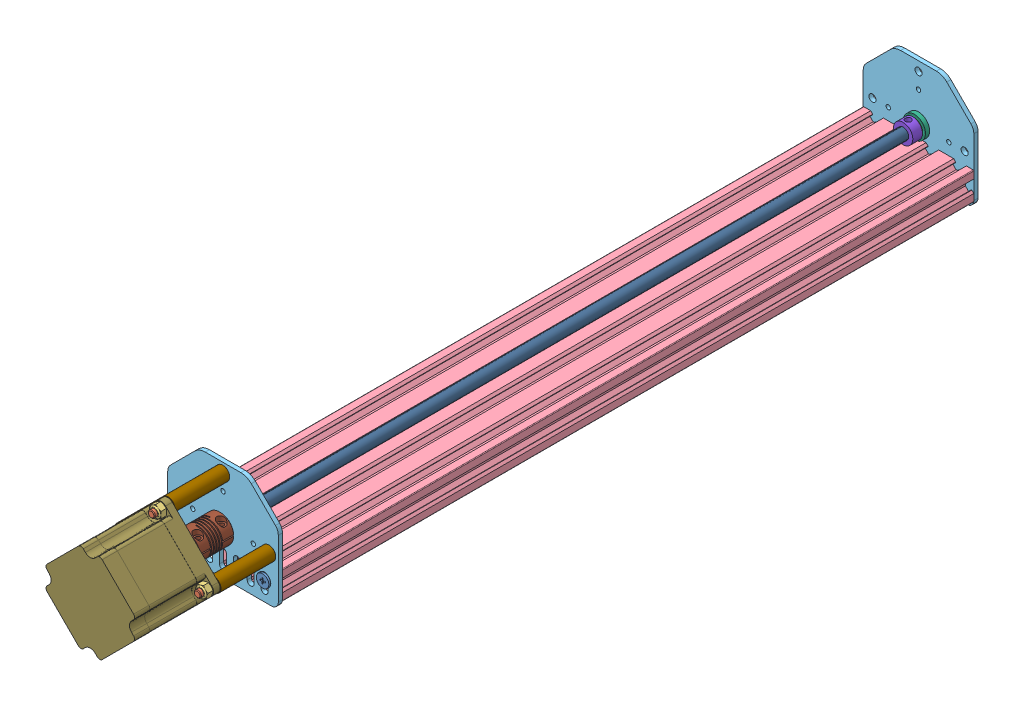
SolidWorks assembly Nema 23 V Slot Lead Screw Driven Actuator, configuration Default. Lengths in mm.
Overall size (80.26 79.88 603.4).
25 component instances, 12 part files, 55 mates.
Components (placement in the parent):
- Self Tapping Screw-1: Self Tapping Screw [Default] at (-30 0 503) x (-1 0 0) z (0 1 0) size (9.6 20.4 9.6)
- Self Tapping Screw-3: Self Tapping Screw [Default] at (30 0 503) x (-1 0 0) z (0 1 0) size (9.6 20.4 9.6)
- Self Tapping Screw-4: Self Tapping Screw [Default] at (30 0 -3) x (1 0 0) z (0 1 0) size (9.6 20.4 9.6)
- Self Tapping Screw-6: Self Tapping Screw [Default] at (-30 0 -3) x (1 0 0) z (0 1 0) size (9.6 20.4 9.6)
- Low Profile Screw M5-11: Low Profile Screw M5 [M5 x 55] at (33.333 18.57 555) x (0 0 1) z (-1 0 0) size (56.62 9 9)
- Low Profile Screw M5-12: Low Profile Screw M5 [M5 x 55] at (0 51.903 555) x (0 0 1) z (-1 0 0) size (56.62 9 9)
- Low Profile Screw M5-13: Low Profile Screw M5 [M5 x 55] at (-33.333 18.57 555) x (0 0 1) z (-1 0 0) size (56.62 9 9)
- Nylon Insert Lock Nut M5-3: Nylon Insert Lock Nut M5 [Default] at (33.333 18.57 547.8) x (0.963541 -0.267562 0) z (-0.267562 -0.963541 0) size (8 5 9.24)
- Nylon Insert Lock Nut M5-4: Nylon Insert Lock Nut M5 [Default] at (0 51.903 547.8) x (1 0 0) z (0 -1 0) size (8 5 9.24)
- Nylon Insert Lock Nut M5-5: Nylon Insert Lock Nut M5 [Default] at (-33.333 18.57 547.8) x (1 0 0) z (0 -1 0) size (8 5 9.24)
- V-Slot 20x80x500 Linear Rail-1: V-Slot 20x80x500 Linear Rail [Default] x (0 -1 0) z (0 0 1) size (20 80 500)
- Threaded Rod Plate Nema 23-2: Threaded Rod Plate Nema 23 [Default] at (0 18.57 503) x (-1 0 0) z (0 -1 0) size (80 3 72.5)
- Threaded Rod Plate Nema 23-3: Threaded Rod Plate Nema 23 [Default] at (0 18.57 -3) x (1 0 0) z (0 -1 0) size (80 3 72.5)
- Ball Bearing 8 x 16 x 5-1: Ball Bearing 8 x 16 x 5 [Default] at (0 18.57 0.5) x (0 0 1) z (-0.957169 -0.289529 0) size (5 16 16)
- Ball Bearing 8 x 16 x 5-2: Ball Bearing 8 x 16 x 5 [Default] at (0 18.57 499.5) x (0 0 1) z (0.959032 0.283297 0) size (5 16 16)
- Shim Washer 8mm-1: Shim Washer 8mm [Default] at (0 18.57 3) x (0.504051 0.863674 0) z (0.863674 -0.504051 0) size (11.8 1.15 11.8)
- Shim Washer 8mm-2: Shim Washer 8mm [Default] at (0 18.57 497) x (-0.37401 -0.927425 0) z (0.927425 -0.37401 0) size (11.8 1.15 11.8)
- Lock Collar 8mm-1: Lock Collar 8mm [Default] at (0 18.57 488.85) size (14 14 7)
- Lock Collar 8mm-2: Lock Collar 8mm [Default] at (0 18.57 4.15) size (14 14 7)
- Aluminum Spacer 40mm-4: Aluminum Spacer 40mm [Default] at (-33.333 18.57 503) x (0.854977 0.518666 0) z (0 0 1) size (10 10 40)
- Aluminum Spacer 40mm-5: Aluminum Spacer 40mm [Default] at (0 51.903 503) x (0.998694 -0.051087 0) z (0 0 1) size (10 10 40)
- Aluminum Spacer 40mm-3: Aluminum Spacer 40mm [Default] at (33.333 18.57 503) x (0.890209 0.455552 0) z (0 0 1) size (10 10 40)
- 8mm leadscrew 520mm-1: 8mm leadscrew 520mm [Default] at (0 18.57 -3) size (8 8 520)
- Flexible Coupling 0.25in x 8mm-1: Flexible Coupling 0.25in x 8mm [Default] at (0 18.57 530) x (0.999321 0.036837 0) z (0 0 1) size (21.03 20 25)
- Nema 23 Stepper Motor-1: Nema 23 Stepper Motor [Default] at (0 18.57 543) x (0.707107 -0.707107 0) z (0 0 -1) size (56.4 56.4 76.6)
Mates (geometry in assembly coordinates):
- Coincident4: coincident anti-aligned: plane of V-Slot 20x80x500 Linear Rail-1 through (0 0 500) normal (0 0 1); plane of Threaded Rod Plate Nema 23-2 through (35 -8.93 500) normal (0 0 -1)
- Distance4: distance = 3.93 mm aligned: plane of V-Slot 20x80x500 Linear Rail-1 through (0 -10 500) normal (0 -1 0); plane of Threaded Rod Plate Nema 23-2 through (-35 -13.93 500) normal (0 -1 0)
- Coincident6: coincident anti-aligned: plane of V-Slot 20x80x500 Linear Rail-1 through (0 0 0) normal (1 0 0); plane of Threaded Rod Plate Nema 23-2 through (0 18.57 503) normal (-1 0 0)
- Coincident7: coincident anti-aligned: plane of V-Slot 20x80x500 Linear Rail-1 through (0 0 0) normal (0 0 -1); plane of Threaded Rod Plate Nema 23-3 through (-35 -8.93 0) normal (0 0 1)
- Distance3: distance = 3.93 mm aligned: plane of V-Slot 20x80x500 Linear Rail-1 through (0 -10 500) normal (0 -1 0); plane of Threaded Rod Plate Nema 23-3 through (35 -13.93 0) normal (0 -1 0)
- Coincident9: coincident aligned: plane of V-Slot 20x80x500 Linear Rail-1 through (0 0 0) normal (1 0 0); plane of Threaded Rod Plate Nema 23-3 through (0 18.57 -3) normal (1 0 0)
- Concentric1: concentric anti-aligned: cylinder of Threaded Rod Plate Nema 23-3 through (0 18.57 0) axis (0 0 -1) radius 5.5; cylinder of Ball Bearing 8 x 16 x 5-1 through (0 18.57 0.5) axis (0 0 1) radius 8
- Coincident10: coincident anti-aligned: plane of Threaded Rod Plate Nema 23-3 through (0 18.57 -2) normal (0 0 1); plane of Ball Bearing 8 x 16 x 5-1 through (-2.0846 25.4616 -2) normal (0 0 -1)
- Concentric2: concentric anti-aligned: cylinder of Threaded Rod Plate Nema 23-2 through (0 18.57 502) axis (0 0 -1) radius 8.025; cylinder of Ball Bearing 8 x 16 x 5-2 through (0 18.57 499.5) axis (0 0 1) radius 8
- Coincident11: coincident anti-aligned: plane of Threaded Rod Plate Nema 23-2 through (0 18.57 502) normal (0 0 -1); plane of Ball Bearing 8 x 16 x 5-2 through (2.0397 11.665 502) normal (0 0 1)
- Concentric3: concentric anti-aligned: cylinder of Ball Bearing 8 x 16 x 5-1 through (0 18.57 0.5) axis (0 0 1) radius 5.1; cylinder of Shim Washer 8mm-1 through (0 18.57 4.15) axis (0 0 -1) radius 4.25
- Coincident12: coincident anti-aligned: plane of Ball Bearing 8 x 16 x 5-1 through (-1.1581 22.3987 3) normal (0 0 1); plane of Shim Washer 8mm-1 through (0 18.57 3) normal (0 0 -1)
- Concentric4: concentric aligned: cylinder of Ball Bearing 8 x 16 x 5-2 through (0 18.57 499.5) axis (0 0 1) radius 4; cylinder of Shim Washer 8mm-2 through (0 18.57 495.85) axis (0 0 1) radius 4.25
- Coincident13: coincident anti-aligned: plane of Ball Bearing 8 x 16 x 5-2 through (1.1332 14.7339 497) normal (0 0 -1); plane of Shim Washer 8mm-2 through (0 18.57 497) normal (0 0 1)
- Concentric5: concentric anti-aligned: cylinder of Shim Washer 8mm-2 through (0 18.57 495.85) axis (0 0 1) radius 5.9; cylinder of Lock Collar 8mm-1 through (0 18.57 495.85) axis (0 0 -1) radius 4
- Coincident14: coincident anti-aligned: plane of Shim Washer 8mm-2 through (0 18.57 495.85) normal (0 0 -1); plane of Lock Collar 8mm-1 through (0 18.57 495.85) normal (0 0 1)
- Concentric6: concentric aligned: cylinder of Shim Washer 8mm-1 through (0 18.57 4.15) axis (0 0 -1) radius 4.25; cylinder of Lock Collar 8mm-2 through (0 18.57 11.15) axis (0 0 -1) radius 4
- Coincident15: coincident anti-aligned: plane of Shim Washer 8mm-1 through (0 18.57 4.15) normal (0 0 1); plane of Lock Collar 8mm-2 through (0 18.57 4.15) normal (0 0 -1)
- Parallel1: parallel aligned: plane of Lock Collar 8mm-1 through (0 18.57 488.85) normal (0 1 0); plane of assembly through (0 0 0) normal (0 1 0)
- Parallel2: parallel aligned: plane of Lock Collar 8mm-2 through (0 18.57 4.15) normal (0 1 0); plane of assembly through (0 0 0) normal (0 1 0)
- Concentric7: concentric anti-aligned: cylinder of V-Slot 20x80x500 Linear Rail-1 through (-30 0 500) axis (0 0 -1) radius 2.1; cylinder of Self Tapping Screw-1 through (-30 0 484) axis (0 0 1) radius 2.425
- Coincident18: coincident anti-aligned: plane of Threaded Rod Plate Nema 23-2 through (35 -8.93 503) normal (0 0 1); plane of Self Tapping Screw-1 through (-27.575 0 503) normal (0 0 -1)
- Concentric91: concentric anti-aligned: cylinder of V-Slot 20x80x500 Linear Rail-1 through (30 0 500) axis (0 0 -1) radius 2.1; cylinder of Self Tapping Screw-3 through (30 0 484) axis (0 0 1) radius 2.425
- Coincident201: coincident anti-aligned: plane of Threaded Rod Plate Nema 23-2 through (35 -8.93 503) normal (0 0 1); plane of Self Tapping Screw-3 through (32.425 0 503) normal (0 0 -1)
- Concentric10: concentric anti-aligned: cone of Aluminum Spacer 40mm-4 through (-33.333 18.57 503.2) axis (0 0 -1); cylinder of Threaded Rod Plate Nema 23-2 through (-33.333 18.57 500) axis (0 0 1) radius 2.55
- Coincident21: coincident anti-aligned: plane of Threaded Rod Plate Nema 23-2 through (35 -8.93 503) normal (0 0 1); plane of Aluminum Spacer 40mm-4 through (-33.333 18.57 503) normal (0 0 -1)
- Concentric11: concentric anti-aligned: cone of Aluminum Spacer 40mm-5 through (0 51.903 503.2) axis (0 0 -1); cylinder of Threaded Rod Plate Nema 23-2 through (0 51.903 500) axis (0 0 1) radius 2.55
- Coincident22: coincident anti-aligned: plane of Threaded Rod Plate Nema 23-2 through (35 -8.93 503) normal (0 0 1); plane of Aluminum Spacer 40mm-5 through (0 51.903 503) normal (0 0 -1)
- Concentric12: concentric anti-aligned: cone of Aluminum Spacer 40mm-3 through (33.333 18.57 503.2) axis (0 0 -1); cylinder of Threaded Rod Plate Nema 23-2 through (33.333 18.57 500) axis (0 0 1) radius 2.55
- Coincident23: coincident anti-aligned: plane of Threaded Rod Plate Nema 23-2 through (35 -8.93 503) normal (0 0 1); plane of Aluminum Spacer 40mm-3 through (33.333 18.57 503) normal (0 0 -1)
- Concentric191: concentric aligned: cylinder of Self Tapping Screw-4 through (30 0 16) axis (0 0 -1) radius 2.425; cylinder of V-Slot 20x80x500 Linear Rail-1 through (30 0 500) axis (0 0 -1) radius 2.1
- Coincident281: coincident anti-aligned: plane of Threaded Rod Plate Nema 23-3 through (-35 -8.93 -3) normal (0 0 -1); plane of Self Tapping Screw-4 through (27.575 0 -3) normal (0 0 1)
- Concentric211: concentric aligned: cylinder of Self Tapping Screw-6 through (-30 0 16) axis (0 0 -1) radius 2.425; cylinder of V-Slot 20x80x500 Linear Rail-1 through (-30 0 500) axis (0 0 -1) radius 2.1
- Coincident301: coincident anti-aligned: plane of Threaded Rod Plate Nema 23-3 through (-35 -8.93 -3) normal (0 0 -1); plane of Self Tapping Screw-6 through (-32.425 0 -3) normal (0 0 1)
- Concentric23: concentric anti-aligned: cylinder of Ball Bearing 8 x 16 x 5-2 through (0 18.57 499.5) axis (0 0 1) radius 4; cylinder of 8mm leadscrew 520mm-1 through (0 18.57 517) axis (0 0 -1) radius 4
- Coincident31: coincident aligned: plane of Threaded Rod Plate Nema 23-3 through (-35 -8.93 -3) normal (0 0 -1); plane of 8mm leadscrew 520mm-1 through (0 18.57 -3) normal (0 0 -1)
- Parallel13: parallel anti-aligned: plane of Threaded Rod Plate Nema 23-2 through (-35 -13.93 500) normal (0 -1 0); plane of Self Tapping Screw-3 through (30 0 503) normal (0 1 0)
- Parallel15: parallel anti-aligned: plane of Threaded Rod Plate Nema 23-2 through (-35 -13.93 500) normal (0 -1 0); plane of Self Tapping Screw-1 through (-30 0 503) normal (0 1 0)
- Concentric432: concentric aligned: cylinder of 8mm leadscrew 520mm-1 through (0 18.57 517) axis (0 0 -1) radius 4; cylinder of Flexible Coupling 0.25in x 8mm-1 through (0 18.57 517.5) axis (0 0 -1) radius 4
- Distance5: distance = 2 mm anti-aligned: plane of Flexible Coupling 0.25in x 8mm-1 through (0 18.57 505) normal (0 0 -1); plane of Threaded Rod Plate Nema 23-2 through (35 -8.93 503) normal (0 0 1)
- Concentric433: concentric anti-aligned: cone of Aluminum Spacer 40mm-4 through (-33.333 18.57 543) axis (0 0 1); cylinder of Nema 23 Stepper Motor-1 through (-33.333 18.57 599.001) axis (0 0 -1) radius 2.55
- Coincident546: coincident anti-aligned: plane of Aluminum Spacer 40mm-4 through (-33.333 18.57 543) normal (0 0 1); plane of Nema 23 Stepper Motor-1 through (-33.3754 18.57 543) normal (0 0 -1)
- Concentric434: concentric aligned: cylinder of Aluminum Spacer 40mm-5 through (0 51.903 543) axis (0 0 -1) radius 2.55; cylinder of Nema 23 Stepper Motor-1 through (0 51.903 599.001) axis (0 0 -1) radius 2.55
- Concentric4351: concentric aligned: cylinder of Threaded Rod Plate Nema 23-2 through (33.333 18.57 500) axis (0 0 1) radius 2.55; cylinder of Low Profile Screw M5-11 through (33.333 18.57 500) axis (0 0 1) radius 2.5
- Coincident5471: coincident anti-aligned: plane of Threaded Rod Plate Nema 23-2 through (35 -8.93 500) normal (0 0 -1); plane of Low Profile Screw M5-11 through (33.333 22.7314 500) normal (0 0 1)
- Concentric4361: concentric aligned: cylinder of Threaded Rod Plate Nema 23-2 through (0 51.903 500) axis (0 0 1) radius 2.55; cylinder of Low Profile Screw M5-12 through (0 51.903 500) axis (0 0 1) radius 2.5
- Coincident5481: coincident anti-aligned: plane of Threaded Rod Plate Nema 23-2 through (35 -8.93 500) normal (0 0 -1); plane of Low Profile Screw M5-12 through (0 56.0645 500) normal (0 0 1)
- Concentric4371: concentric aligned: cylinder of Threaded Rod Plate Nema 23-2 through (-33.333 18.57 500) axis (0 0 1) radius 2.55; cylinder of Low Profile Screw M5-13 through (-33.333 18.57 500) axis (0 0 1) radius 2.5
- Coincident5491: coincident anti-aligned: plane of Threaded Rod Plate Nema 23-2 through (35 -8.93 500) normal (0 0 -1); plane of Low Profile Screw M5-13 through (-33.333 22.7314 500) normal (0 0 1)
- Concentric4381: concentric aligned: cylinder of Nema 23 Stepper Motor-1 through (0 51.903 599.001) axis (0 0 -1) radius 2.55; cylinder of Nylon Insert Lock Nut M5-4 through (0 51.903 547.8) axis (0 0 -1) radius 2.5
- Coincident5501: coincident anti-aligned: plane of Nema 23 Stepper Motor-1 through (-33.3754 18.57 547.8) normal (0 0 1); plane of Nylon Insert Lock Nut M5-4 through (-2.5 51.903 547.8) normal (0 0 -1)
- Concentric4391: concentric aligned: cylinder of Nema 23 Stepper Motor-1 through (-33.333 18.57 599.001) axis (0 0 -1) radius 2.55; cylinder of Nylon Insert Lock Nut M5-5 through (-33.333 18.57 547.8) axis (0 0 -1) radius 2.5
- Coincident5511: coincident anti-aligned: plane of Nema 23 Stepper Motor-1 through (-33.3754 18.57 547.8) normal (0 0 1); plane of Nylon Insert Lock Nut M5-5 through (-35.833 18.57 547.8) normal (0 0 -1)
- Concentric440: concentric aligned: cylinder of Nema 23 Stepper Motor-1 through (33.333 18.57 599.001) axis (0 0 -1) radius 2.55; cylinder of Nylon Insert Lock Nut M5-3 through (33.333 18.57 547.8) axis (0 0 -1) radius 2.5
- Coincident552: coincident anti-aligned: plane of Nema 23 Stepper Motor-1 through (-33.3754 18.57 547.8) normal (0 0 1); plane of Nylon Insert Lock Nut M5-3 through (30.9242 19.2389 547.8) normal (0 0 -1)
